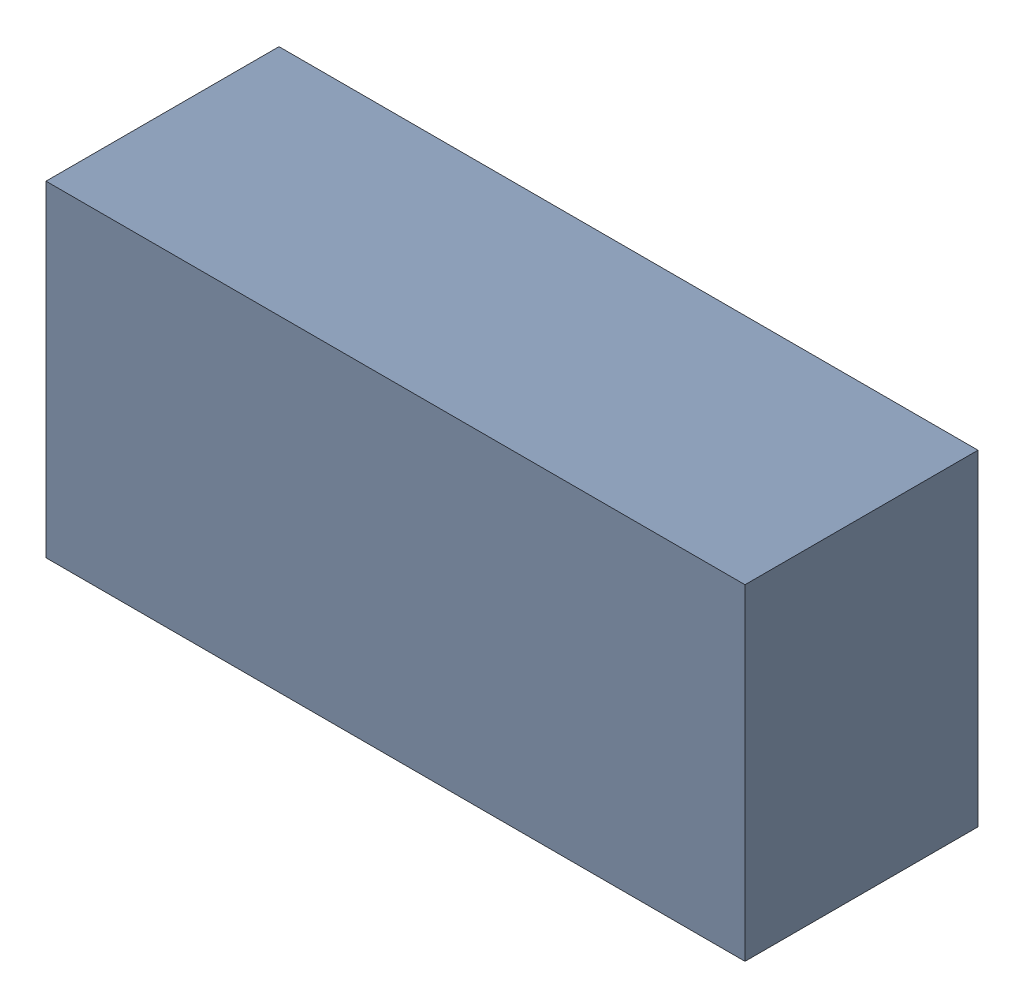
SolidWorks assembly Q1-2, configuration Default. Lengths in mm.
Overall size (3 1.4 1).
2 component instances, 1 part files, 0 mates.
Components (placement in the parent):
- 959206488-2-1: 959206488-2 [Default] at (75.057 92.3634 0.1) size (3 1.4 1)
  - Extruded-73-1: Extruded-73 [Default] at origin size (3 1.4 1)
